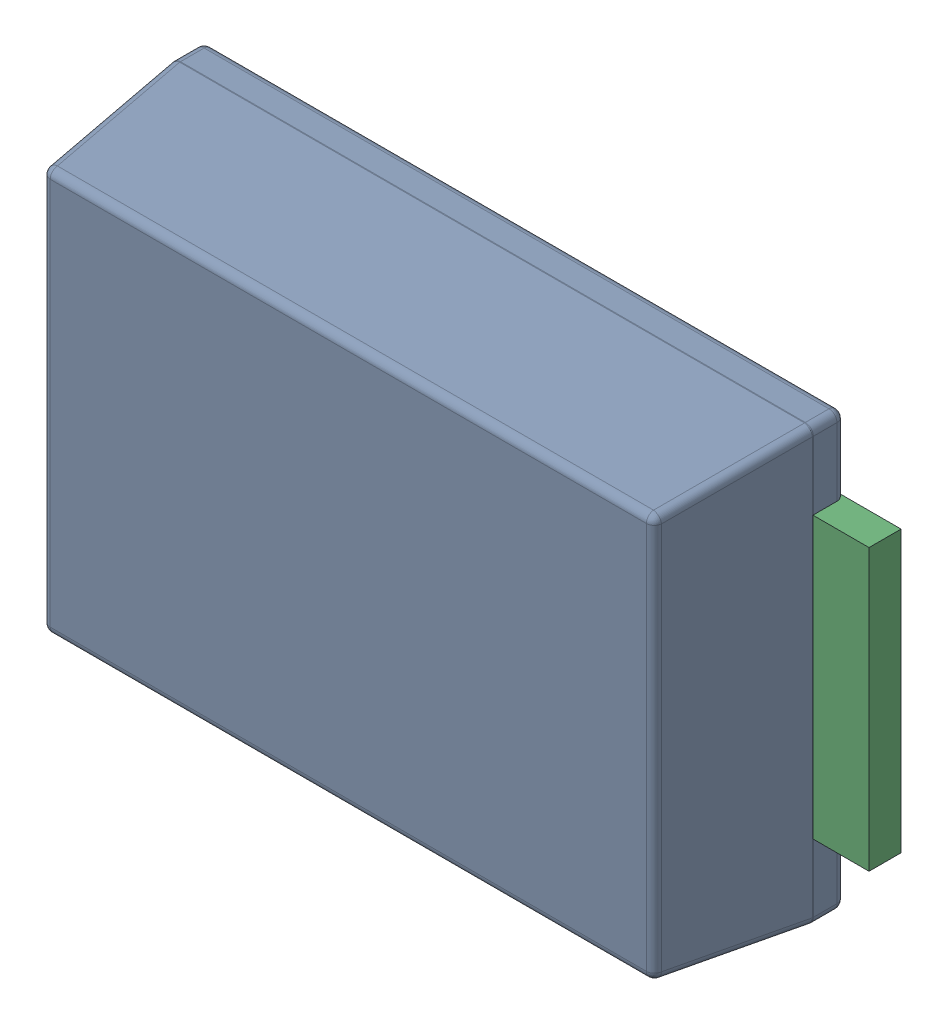
SolidWorks assembly 1281330688, configuration Default. Lengths in mm.
Overall size (4.7 2.71 1.1).
4 component instances, 2 part files, 0 mates.
Components (placement in the parent):
- Body-1: Body [Default] at (-2 -1.35 0) size (4.01 2.71 1.1)
  - Open_CASCADE_STEP_translator_6.8_1.1.1-1: Open_CASCADE_STEP_translator_6.8_1.1.1 [Default] at origin size (4.01 2.71 1.1)
- lead-1: lead [Default] at (-2.35 -0.875 0) size (0.72 1.75 0.2)
- lead-2: lead [Default] at (2.35 0.875 0) x (-1 0 0) z (0 0 1) size (0.72 1.75 0.2)
